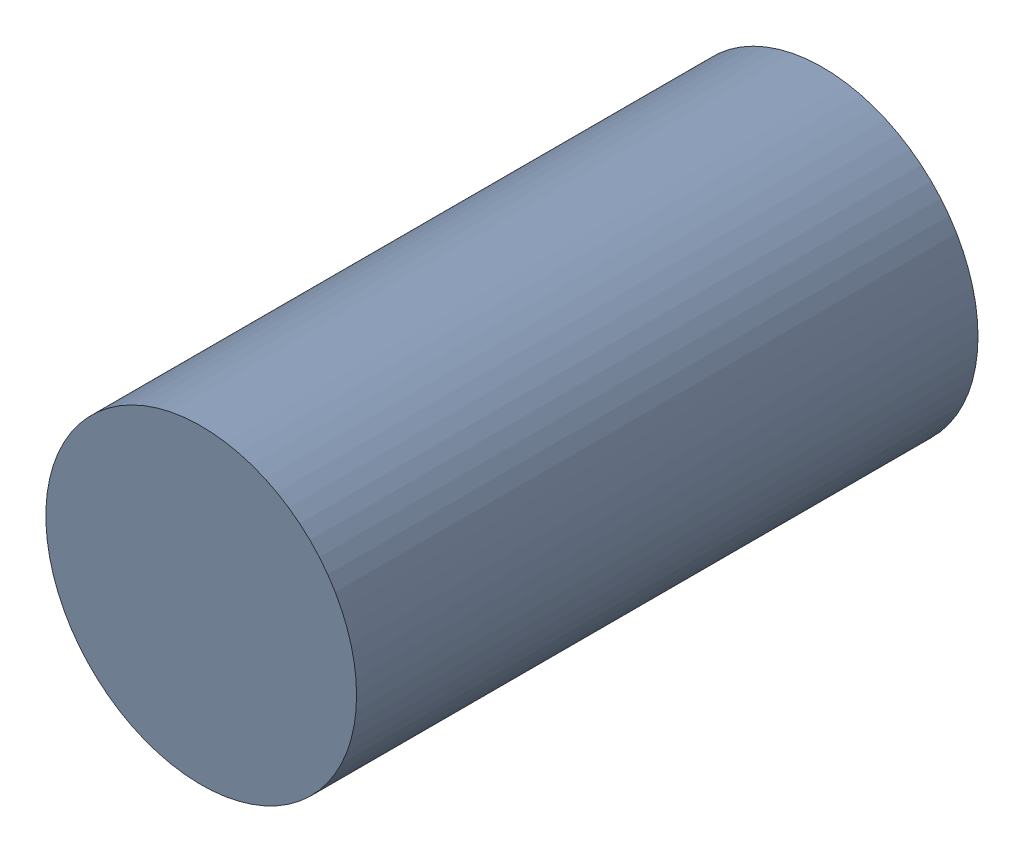
SolidWorks assembly MH12_1.step, configuration Default. Lengths in mm.
Overall size (1 1 2).
2 component instances, 1 part files, 0 mates.
Components (placement in the parent):
- 9228463120_1.step-11: 9228463120_1.step [Default] at (433.1523 311.7064 -1.5) size (1 1 2)
  - Cylinder_1.step-98: Cylinder_1.step [Default] at origin size (1 1 2)
